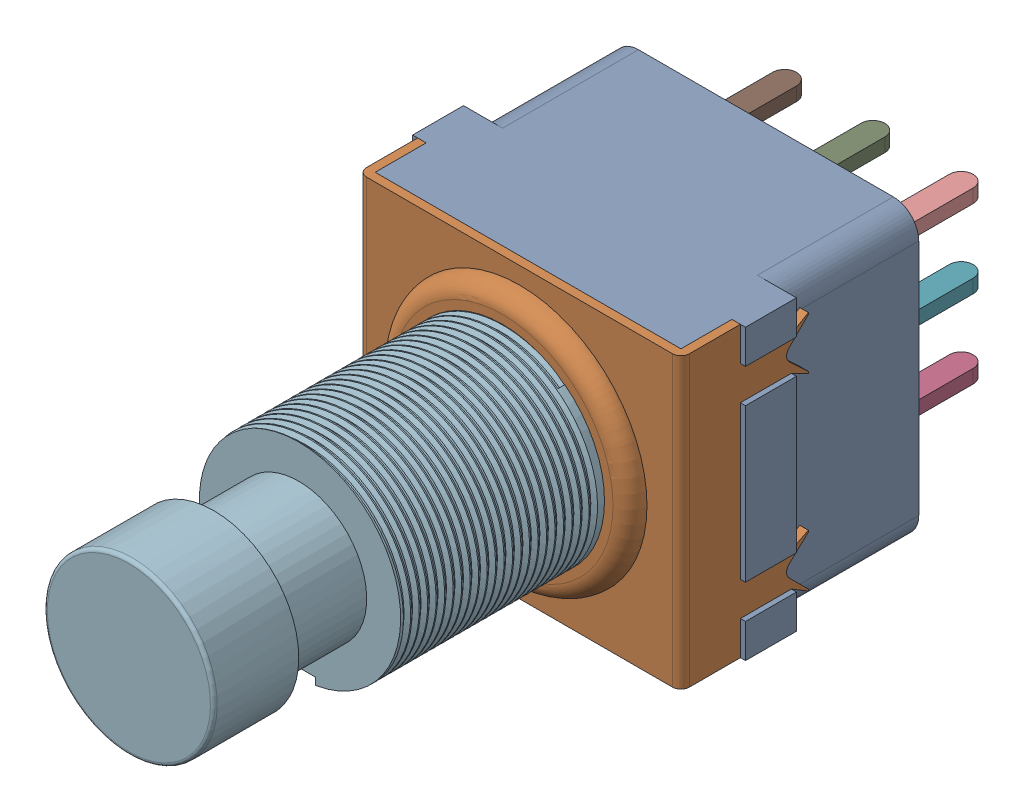
SolidWorks assembly FSW1, configuration Default. Lengths in mm.
Overall size (19.6 17 44.5).
13 component instances, 4 part files, 0 mates.
Components (placement in the parent):
- 3PDT-1: 3PDT [Default] at (30.2994 72.0412 1.27) x (1 0 0) z (0 0 1) size (19.6 17 44.5)
  - 3PDT Body-1: 3PDT Body [Default] at (0 -2.1806 0.7727) size (19.6 17 15)
  - 3PDT Cover-1: 3PDT Cover [Default] at (-0.5 14.8194 11.7727) x (1 0 0) z (0 -1 0) size (19 8.5 17)
  - 3PDT Pin-1: 3PDT Pin [Default] at (7 1.7194 0.7727) x (1 0 0) z (0 1 0) size (4 7 0.8)
  - 3PDT Pin-2: 3PDT Pin [Default] at (12.2 1.7194 0.7727) x (1 0 0) z (0 1 0) size (4 7 0.8)
  - 3PDT Pin-3: 3PDT Pin [Default] at (1.8 1.7194 0.7727) x (1 0 0) z (0 1 0) size (4 7 0.8)
  - 3PDT Pin-4: 3PDT Pin [Default] at (7 6.3194 0.7727) x (1 0 0) z (0 1 0) size (4 7 0.8)
  - 3PDT Pin-5: 3PDT Pin [Default] at (12.2 6.3194 0.7727) x (1 0 0) z (0 1 0) size (4 7 0.8)
  - 3PDT Pin-6: 3PDT Pin [Default] at (1.8 6.3194 0.7727) x (1 0 0) z (0 1 0) size (4 7 0.8)
  - 3PDT Pin-7: 3PDT Pin [Default] at (7 10.9194 0.7727) x (1 0 0) z (0 1 0) size (4 7 0.8)
  - 3PDT Pin-8: 3PDT Pin [Default] at (12.2 10.9194 0.7727) x (1 0 0) z (0 1 0) size (4 7 0.8)
  - 3PDT Pin-9: 3PDT Pin [Default] at (1.8 10.9194 0.7727) x (1 0 0) z (0 1 0) size (4 7 0.8)
  - 3PDT Schalter-1: 3PDT Schalter [Default] at (9 6.3194 28.2727) x (0 -1 0) z (0 0 1) size (12 12.17 22.2)
